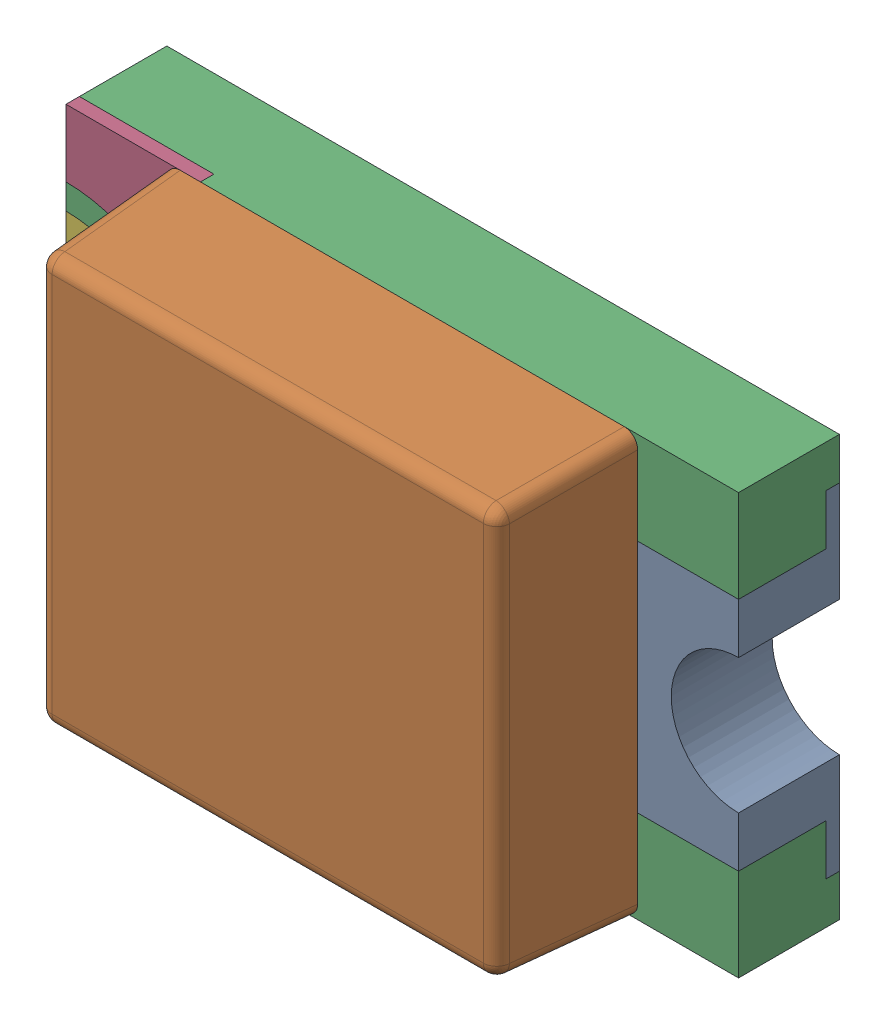
SolidWorks assembly D5, configuration Standard. Lengths in mm.
Overall size (2 1.25 0.7).
7 component instances, 5 part files, 0 mates.
Components (placement in the parent):
- WL-SMCW_0805_LED-1: WL-SMCW_0805_LED [Standard] at (12.1102 24.4202 -0.02) x (1 0 0) z (0 0 1) size (2 1.25 0.7)
  - base-1: base [Standard] at (0.8 0 0) x (-1 0 0) z (0 0 1) size (0.4 1 0.3)
  - cover-1: cover [Standard] at (0 0 0.3) size (1.4 1.25 0.4)
  - housing_3-1: housing_3 [Standard] at origin size (2 1.25 0.3)
  - marking-1: marking [Standard] at (-0.8 0.525 0.26) size (0.4 0.48 0.04)
  - marking-2: marking [Standard] at (-0.8 -0.525 0.3) x (1 0 0) z (0 0 -1) size (0.4 0.48 0.04)
  - base_2-1: base_2 [Standard] at (-0.8 0 0) size (0.4 1 0.3)
